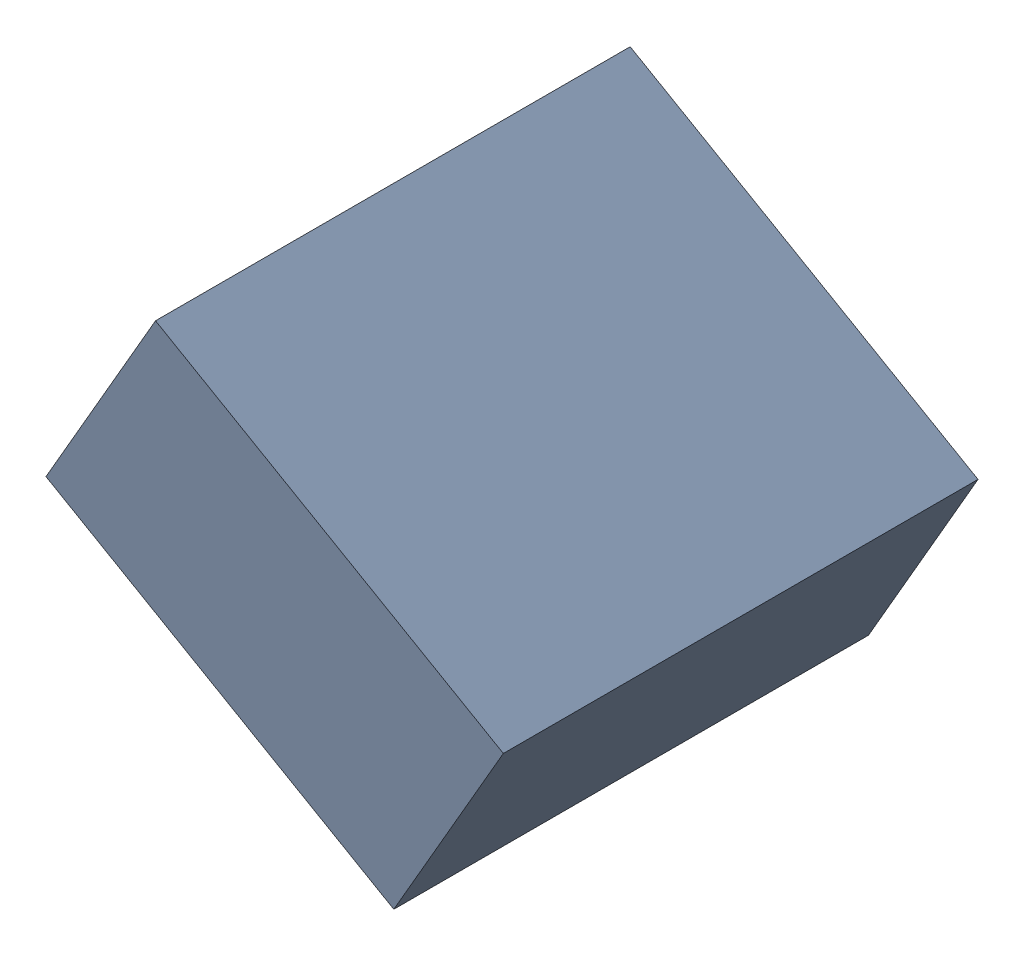
SolidWorks assembly C27_TDA3, configuration Standard. Lengths in mm.
Overall size (1.25 1.07 1.3).
2 component instances, 1 part files, 0 mates.
Components (placement in the parent):
- 885543056-1: 885543056 [Standard] at (47.7341 -32.2133 0) size (1.25 1.07 1.3)
  - Extruded_23-1: Extruded_23 [Standard] at origin size (1.25 1.07 1.3)
